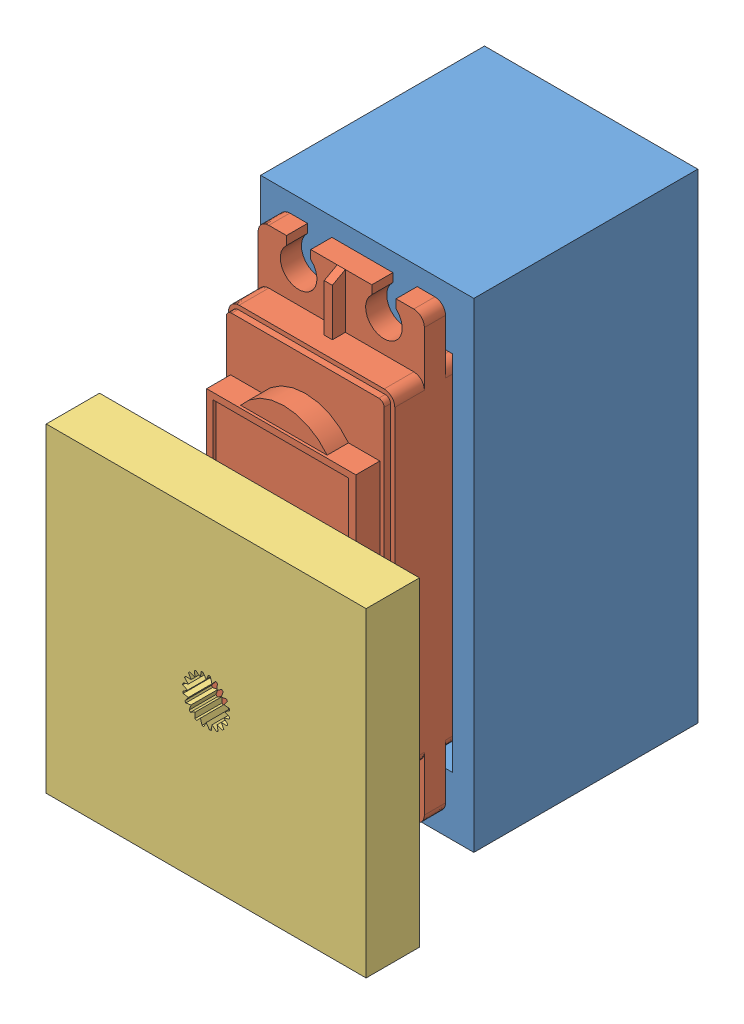
SolidWorks assembly Turret_Assm, configuration Default. Lengths in mm.
Overall size (38.1 60.39 45.32).
3 component instances, 3 part files, 9 mates.
Components (placement in the parent):
- Turret_Base-1: Turret_Base [Default] at origin size (25.4 57.15 26.67)
- hs-422_sws-1: hs-422_sws [Default] at (-10.4838 0 20.701) x (1 0 0) z (0 -1 0) size (19.81 42.14 58.23)
- Turret_Plate-1: Turret_Plate [Default] at (-0.5778 -10.287 38.9255) x (-1 0 0) z (0 1 0) size (38.1 6.35 38.1)
Mates (geometry in assembly coordinates):
- Coincident3: coincident: plane of assembly through (0 0 0) normal (0 0 1); plane of Turret_Base-1 through (0 0 0) normal (0 0 1); plane of assembly
- Coincident4: coincident: plane of assembly through (0 0 0) normal (0 1 0); plane of Turret_Base-1 through (0 0 0) normal (0 1 0); plane of assembly
- Coincident5: coincident: plane of assembly through (0 0 0) normal (1 0 0); plane of Turret_Base-1 through (0 0 0) normal (1 0 0); plane of assembly
- Coincident6: coincident anti-aligned: plane of Turret_Base-1 through (0 0 26.67) normal (0 0 1); plane of hs-422_sws-1 through (9.3282 0 26.67) normal (0 0 -1)
- Distance1: distance = 3.81 mm: plane of Turret_Base-1 through (6.35 28.576 -6.6496) normal (-1 0 0); line of hs-422_sws-1 through (2.54 -21.209 1.651) axis (0 0 1)
- Distance2: distance = 1.651 mm: plane of Turret_Base-1 through (-10.16 -21.59 26.67) normal (0 1 0); cylinder of hs-422_sws-1 through (6.3212 -19.6215 1.905) axis (1 0 0) radius 0.3175
- Coincident8: coincident aligned: circle of hs-422_sws-1; plane of Turret_Plate-1 through (-0.5778 -10.287 38.9255) normal (0 0 -1)
- Parallel1: parallel aligned: plane of Turret_Base-1 through (12.7 -28.575 26.67) normal (0 -1 0); plane of Turret_Plate-1 through (-0.5778 -29.337 45.2755) normal (0 -1 0)
- Coincident9: coincident anti-aligned: line of hs-422_sws-1 through (-1.2649 -12.4015 38.9255) axis (0 0 1); line of Turret_Plate-1 through (-1.2649 -12.4015 45.2755) axis (0 0 -1)
